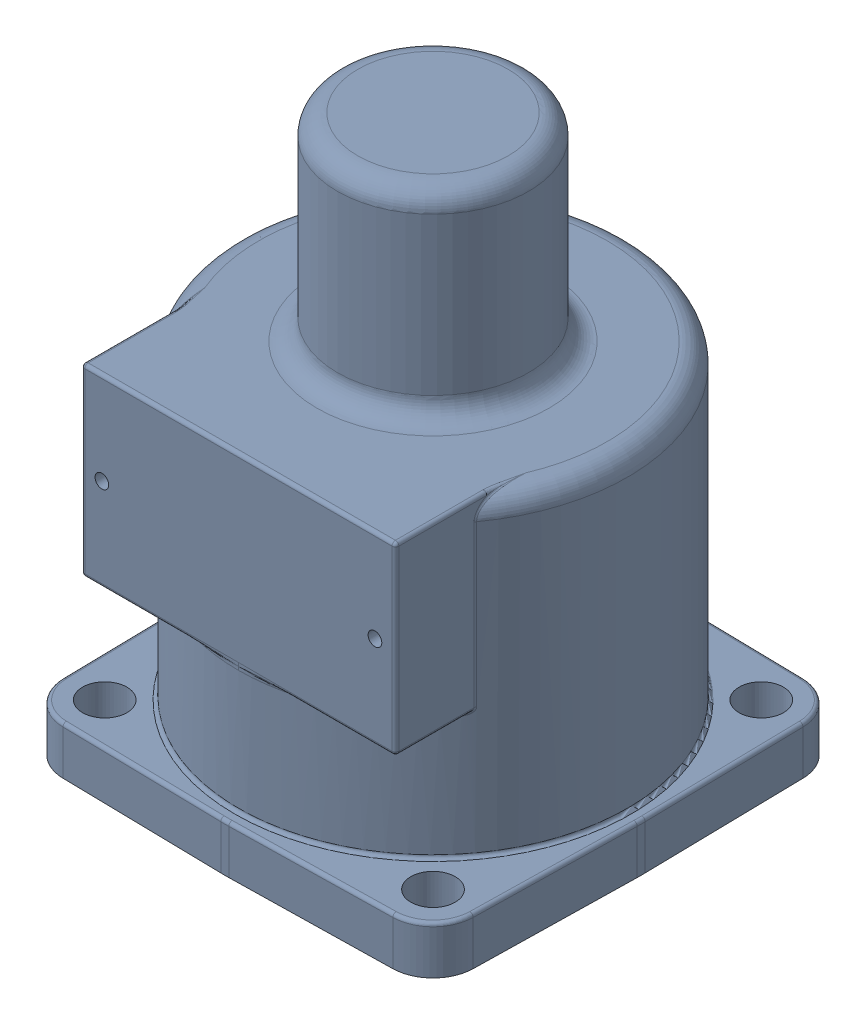
SolidWorks assembly CUP-F25-37RDC-SL, configuration Default. Lengths in mm.
Overall size (96.84 129.38 96.84).
3 component instances, 2 part files, 0 mates.
Components (placement in the parent):
- CUP-F25-37RDC-1: CUP-F25-37RDC [Default] at origin size (96.84 129.38 96.84)
  - CASTING-1544-1: CASTING-1544 [Default] at origin size (96.84 129.38 96.84)
- SLEEVE-33-1: SLEEVE-33 [Default] at (0 46.0756 0) size (31.75 38.89 31.75)
